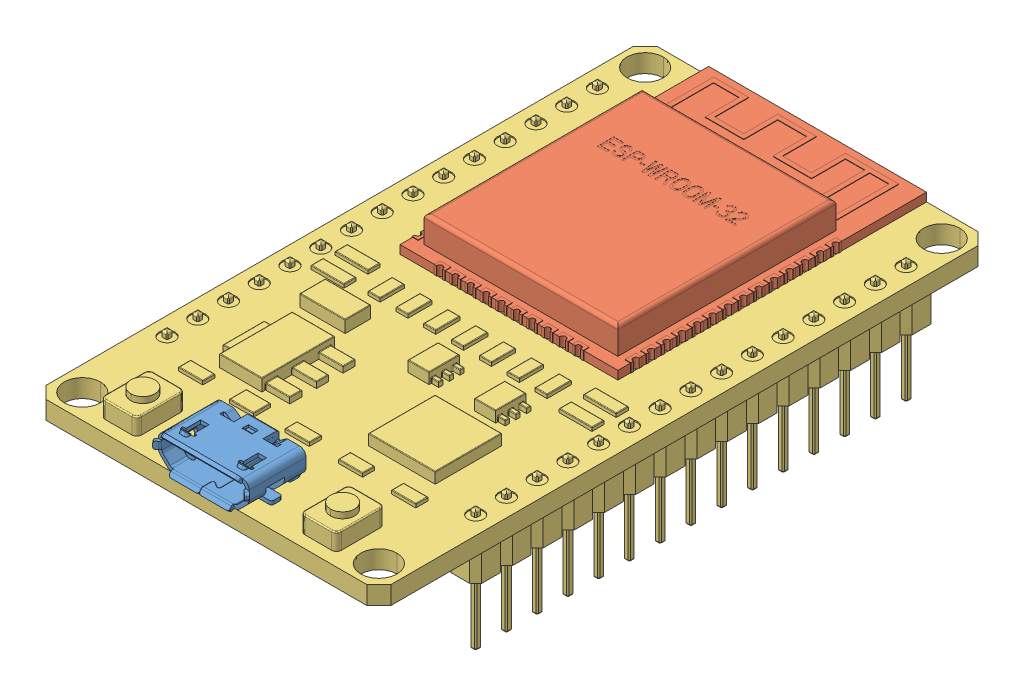
SolidWorks assembly ESP-WROOM32, configuration Standard. Lengths in mm.
Overall size (28.5 12.4 50.93).
4 component instances, 3 part files, 0 mates.
Components (placement in the parent):
- ESP-WROOM32.STEP-1: ESP-WROOM32.STEP [Standard] at origin size (28.5 12.4 50.93)
  - micro_usb_47346-0001.STEP-1: micro_usb_47346-0001.STEP [Standard] at (-1.7662 -0.0714 7.915) size (7.98 2.94 5.43)
  - ESP-WROOM-32.STEP-1: ESP-WROOM-32.STEP [Standard] at (-1.5465 -1.4314 -27.485) x (-1 0 0) z (0 1 0) size (18.07 25.54 3.04)
  - 6.ESP-32_Predeterminado.STEP-1: 6.ESP-32_Predeterminado.STEP [Standard] at (-1.5465 -2.7964 -14.985) size (28.5 11.4 50.5)
